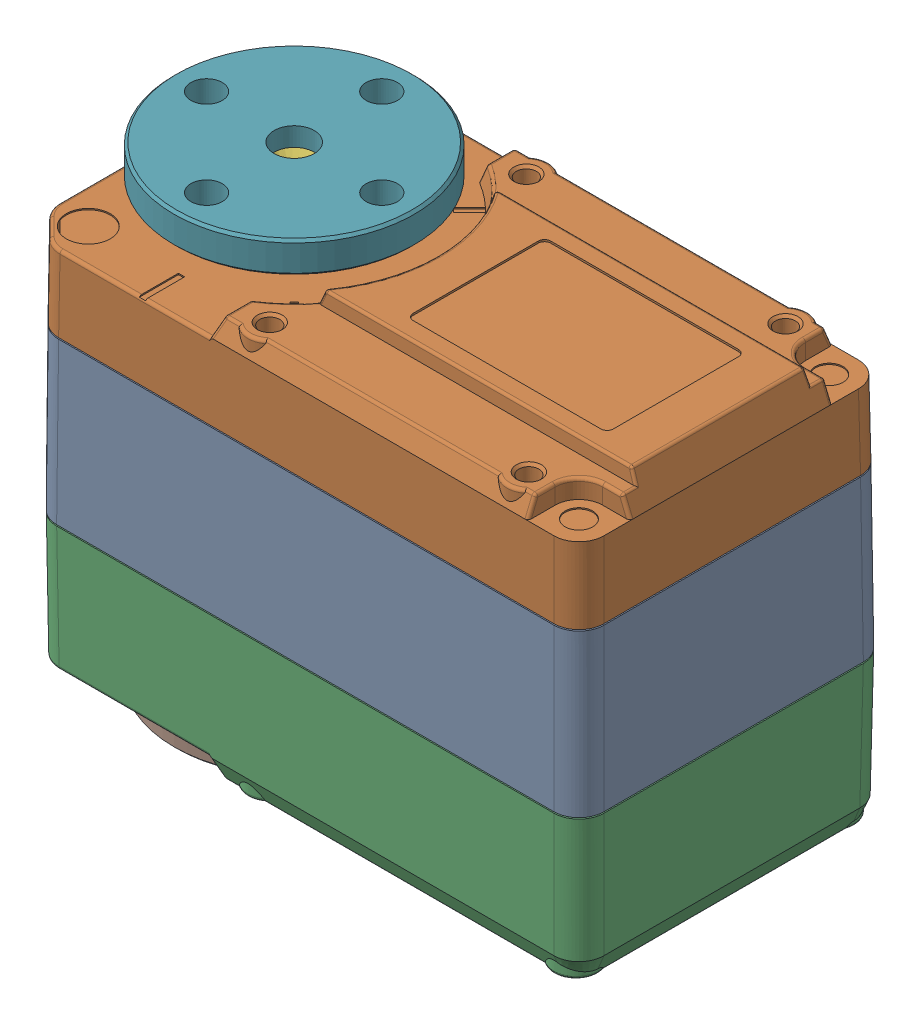
SolidWorks assembly ST3215, configuration Default. Lengths in mm.
Overall size (45.22 37.8 24.72).
8 component instances, 8 part files, 0 mates.
Components (placement in the parent):
- ZK_122-1: ZK_122 [Default] at (47.4834 -4.9003 -26.6402) size (45.22 13.9 24.72)
- SG-ZIJI_15-1: SG-ZIJI_15 [Default] at (47.4834 -4.9003 -26.6402) size (45 9.77 24.5)
- XG-ZIJI_16-1: XG-ZIJI_16 [Default] at (47.4834 -4.9003 -26.6402) size (45.22 14.1 24.72)
- MOTOR-1723_3-1: MOTOR-1723_3 [Default] at (47.4834 -27.7503 -27.8902) x (0 0 -1) z (1 0 0) size (17.05 30.5 17.05)
- PCB-CHAZUO_92-1: PCB-CHAZUO_92 [Default] at (47.4834 -4.9003 -26.6402) size (28.8 7.2 21.1)
- GE_27-1: GE_27 [Default] at (21.9834 -10.9003 -26.6402) x (1 0 0) z (0 -1 0) size (17.6 17.59 18.3)
- 金属舵盘（驱动）-1: 金属舵盘（驱动） [Default] at (11.9834 -22.3003 -26.6402) size (19.2 4.5 19.2)
- 金属舵盘（从动）-1: 金属舵盘（从动） [Default] at (31.9834 -54.3503 -26.6402) x (-1 0 0) z (0 0 1) size (19.2 3.35 19.2)
